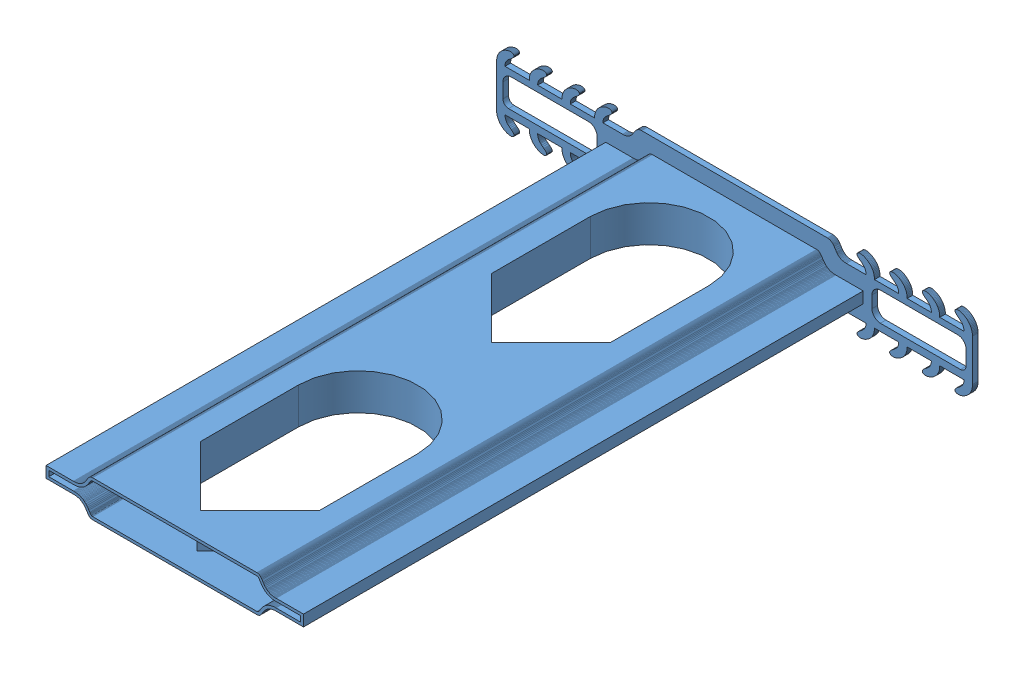
SolidWorks assembly Assem2, configuration Default. Lengths in mm.
Overall size (170 26.08 202).
2 component instances, 2 part files, 3 mates.
Components (placement in the parent):
- buckle_stand_v3_100stack-1: buckle_stand_v3_100stack [Default] at origin size (170 26.08 202)
- buckle_stand_v3 -lid-2: buckle_stand_v3 -lid [Default] at (-0.4938 -0.4938 100) size (170 26.08 10) (hidden)
Mates (geometry in assembly coordinates):
- Coincident2: coincident anti-aligned: plane of buckle_stand_v3_100stack-1 through (0 0 202) normal (0 0 1); plane of buckle_stand_v3 -lid-2 through (-0.4938 -0.4938 202) normal (0 0 -1)
- Coincident3: coincident anti-aligned: plane of buckle_stand_v3_100stack-1 through (0 -5.5 202) normal (0 1 0); plane of buckle_stand_v3 -lid-2 through (28.8384 -5.5 202) normal (0 -1 0)
- Coincident7: coincident anti-aligned: plane of buckle_stand_v3_100stack-1 through (-45 0 202) normal (1 0 0); plane of buckle_stand_v3 -lid-2 through (-45 -1 202) normal (-1 0 0)
